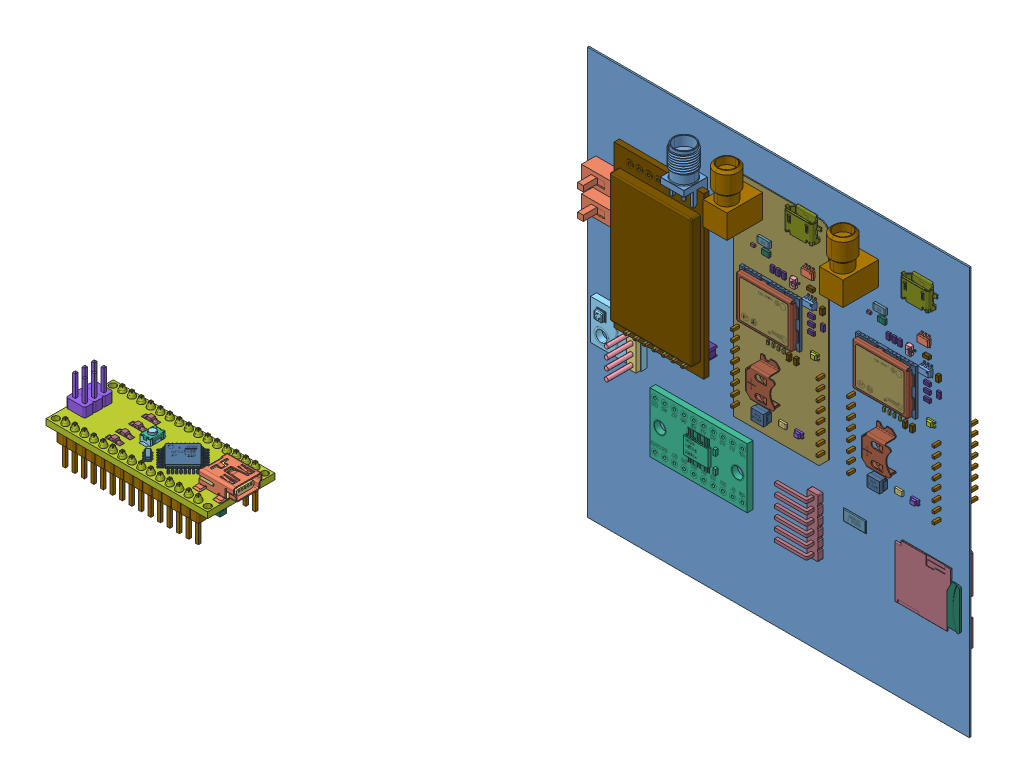
SolidWorks assembly PCB1, configuration Default. Lengths in mm.
Overall size (430.41 167.25 27.02).
258 component instances, 58 part files, 0 mates.
Components (placement in the parent):
- PCB1.step-1: PCB1.step [Default] at (36.6577 -60.7756 -25.2117) size (430.41 167.25 27.02)
  - Board.step-1: Board.step [Default] at origin size (102.11 108.97 0.41)
    - Open CASCADE STEP translator 6.8 2.1.1.step-1: Open CASCADE STEP translator 6.8 2.1.1.step [Default] at (0 0 -0.4115) size (102.11 108.97 0.41)
  - Arduino_Nano.step-1: Arduino_Nano.step [Default] at origin size (45 18.6 18)
    - MINIUSB_-_MEASURED.step-1: MINIUSB_-_MEASURED.step [Default] at (38.98 1.65 -7.62) x (0 0 1) z (-1 0 0) size (10.9 4.8 10.4)
      - MINIUSBSHELL.step-1: MINIUSBSHELL.step [Default] at origin size (10.9 3.75 9.4)
      - MINIUSBCORE.step-1: MINIUSBCORE.step [Default] at (0 0 6.7) x (-1 0 0) z (0 0 -1) size (7.7 4.5 8.2)
      - MINI_USB_CONTACT.step-1: MINI_USB_CONTACT.step [Default] at (-1.6 0 5.7) x (-1 0 0) z (0 0 -1) size (0.51 2.55 9.4)
      - MINI_USB_CONTACT.step-2: MINI_USB_CONTACT.step [Default] at (-0.8 0 5.7) x (-1 0 0) z (0 0 -1) size (0.51 2.55 9.4)
      - MINI_USB_CONTACT.step-3: MINI_USB_CONTACT.step [Default] at (0 0 5.7) x (-1 0 0) z (0 0 -1) size (0.51 2.55 9.4)
      - MINI_USB_CONTACT.step-4: MINI_USB_CONTACT.step [Default] at (0.8 0 5.7) x (-1 0 0) z (0 0 -1) size (0.51 2.55 9.4)
      - MINI_USB_CONTACT.step-5: MINI_USB_CONTACT.step [Default] at (1.6 0 5.7) x (-1 0 0) z (0 0 -1) size (0.51 2.55 9.4)
    - reset_button.step-1: reset_button.step [Default] at (15.25 1.6 -8.05) x (0 0 -1) z (1 0 0) size (5.2 2.15 3)
      - reset_core.step-1: reset_core.step [Default] at origin size (5.2 2.15 2.8)
      - reset_shell.step-1: reset_shell.step [Default] at (0 1.65 0) x (0 0 1) z (-1 0 0) size (3 1.65 4)
    - nano-board.step-1: nano-board.step [Default] at origin size (43.2 4.6 18)
    - 2pin_header__02.step-1: 2pin_header__02.step [Default] at (-1.143 1.6 -7.62) size (5 11.75 2.54)
    - 2pin_header__02.step-2: 2pin_header__02.step [Default] at (-1.143 1.6 -5.08) size (5 11.75 2.54)
    - 2pin_header__02.step-3: 2pin_header__02.step [Default] at (-1.143 1.6 -10.16) size (5 11.75 2.54)
    - 15pin_header__.step-1: 15pin_header__.step [Default] x (0 0 1) z (1 0 0) size (2.54 11.75 38.1)
    - 15pin_header__.step-2: 15pin_header__.step [Default] at (0 0 -15.24) x (0 0 1) z (1 0 0) size (2.54 11.75 38.1)
    - atmega328.step-1: atmega328.step [Default] at (23.85 1.75 -7.62) x (-0.707107 0 0.707107) z (-0.707107 0 -0.707107) size (10 1.1 10)
    - ftdi_FT232rl.step-1: ftdi_FT232rl.step [Default] at (29.05 0 -7.67) x (0 0 -1) z (-1 0 0) size (9.25 1.9 10.2)
    - smt_resistor222.step-1: smt_resistor222.step [Default] at (21.86 0 -5.8) x (0 0 -1) z (-1 0 0) size (1.7 0.6 3.8)
    - smt_resistor222.step-2: smt_resistor222.step [Default] at (21.86 0 -9) x (0 0 -1) z (-1 0 0) size (1.7 0.6 3.8)
    - smt_resistor222.step-3: smt_resistor222.step [Default] at (36.75 0 -7.6) x (0 0 -1) z (-1 0 0) size (1.7 0.6 3.8)
    - smt_resistor222.step-4: smt_resistor222.step [Default] at (36.75 0 -12) x (0 0 -1) z (-1 0 0) size (1.7 0.6 3.8)
    - smt_resistor222.step-5: smt_resistor222.step [Default] at (8.2 0 -2.6) x (0 0 -1) z (-1 0 0) size (1.7 0.6 3.8)
    - led.step-1: led.step [Default] at (10.4 1.6 -2.8) size (4 0.85 1.47)
    - led.step-2: led.step [Default] at (10.4 1.6 -5.55) size (4 0.85 1.47)
    - led.step-3: led.step [Default] at (10.4 1.6 -12.5) size (4 0.85 1.47)
    - led.step-4: led.step [Default] at (10.4 1.6 -9.05) size (4 0.85 1.47)
    - 16mhz_crystal_-_measured.step-1: 16mhz_crystal_-_measured.step [Default] at (18.5113 1.6 -3.5541) x (0.707107 0 0.707107) z (-0.707107 0 0.707107) size (3.4 0.8 2)
    - cap106C.step-1: cap106C.step [Default] at (37.2 0 -3.3) x (0 0 1) z (1 0 0) size (1.7 1.81 4)
    - cap106C.step-2: cap106C.step [Default] at (7.9 0 -5.6) x (0 0 -1) z (-1 0 0) size (1.7 1.81 4)
    - nano_-_reg.step-1: nano_-_reg.step [Default] at (6.1 0 -10.16) x (0 0 -1) z (-1 0 0) size (6.5 1.69 8.3)
    - NANO_DIODE.step-1: NANO_DIODE.step [Default] at (11.43 0 -4.2) x (0 0 1) z (1 0 0) size (4.92 1.39 1.7)
    - 189_RESISTOR_PACK.step-1: 189_RESISTOR_PACK.step [Default] at (15.75 0 -10.85) x (0 0 1) z (1 0 0) size (3.2 0.46 3)
    - 102_RESISTOR_PACK.step-1: 102_RESISTOR_PACK.step [Default] at (15.75 0 -5.2) x (0 0 1) z (1 0 0) size (3.2 0.46 3)
  - M0.step-1: M0.step [Default] at origin size (8.61 3.85 12.07)
    - SS12D00G4_1P2T_Straight.step-1: SS12D00G4_1P2T_Straight.step [Default] at (146.8249 131.405 2.54) x (1 0 0) z (0 0 1) size (8.61 3.85 12.07)
  - BMP.step-1: BMP.step [Default] at origin size (13.52 10.7 12.7)
    - 1185083472.step-1: 1185083472.step [Default] at (154.178 97.536 0) size (2.54 10.16 2.8)
      - Extruded.step-1: Extruded.step [Default] at origin size (2.54 10.16 2.8)
    - 1185083552.step-1: 1185083552.step [Default] at (154.1779 93.7261 -3.2) x (0 1 0) z (0 0 1) size (1.06 1.06 12.7)
      - Cylinder.step-1: Cylinder.step [Default] at origin size (1.06 1.06 12.7)
    - 1185083552.step-2: 1185083552.step [Default] at (154.1779 96.2661 -3.2) x (0 1 0) z (0 0 1) size (1.06 1.06 12.7)
      - Cylinder.step-1: Cylinder.step [Default] at origin size (1.06 1.06 12.7)
    - 1185083552.step-3: 1185083552.step [Default] at (154.1779 98.8061 -3.2) x (0 1 0) z (0 0 1) size (1.06 1.06 12.7)
      - Cylinder.step-1: Cylinder.step [Default] at origin size (1.06 1.06 12.7)
    - 1185083552.step-4: 1185083552.step [Default] at (154.1779 101.3461 -3.2) x (0 1 0) z (0 0 1) size (1.06 1.06 12.7)
      - Cylinder.step-1: Cylinder.step [Default] at origin size (1.06 1.06 12.7)
    - GY-BME280.step-1: GY-BME280.step [Default] at (155.5751 97.6629 0) x (0 1 0) z (0 0 1) size (10.7 13.52 3.64)
  - LVL_CONV.step-1: LVL_CONV.step [Default] at origin size (26 16 2.26)
    - TXS0108E.step-1: TXS0108E.step [Default] at (183.8961 73.6876 0) x (-1 0 0) z (0 1 0) size (26 2.26 16)
  - GPS.step-1: GPS.step [Default] at origin size (219.53 65.66 19.66)
    - GNSS_7_Click_v100_noAntenna.step-1: GNSS_7_Click_v100_noAntenna.step [Default] at (180.3023 96.7993 0.254) x (1 0 0) z (0 0 1) size (219.53 65.66 19.66)
      - GNSS_7_Click_v100.step.step-1: GNSS_7_Click_v100.step.step [Default] at origin size (219.53 65.66 19.66)
        - JP4.step.step-1: JP4.step.step [Default] at origin size (0.5 1 0.35)
          - User_Library-R_0402.step.step-1: User_Library-R_0402.step.step [Default] at (12.3191 18.1685 0) x (0 -1 0) z (0 0 1) size (1 0.5 0.35)
        - JP3.step.step-1: JP3.step.step [Default] at origin size (0.5 1 0.35)
          - User_Library-R_0402.step.step-1: User_Library-R_0402.step.step [Default] at (10.9221 18.161 0) x (0 -1 0) z (0 0 1) size (1 0.5 0.35)
        - JP2.step.step-1: JP2.step.step [Default] at origin size (0.5 1 0.35)
          - User_Library-R_0402.step.step-1: User_Library-R_0402.step.step [Default] at (9.5251 18.1685 0) x (0 -1 0) z (0 0 1) size (1 0.5 0.35)
        - JP1.step.step-1: JP1.step.step [Default] at origin size (0.5 1 0.35)
          - User_Library-R_0402.step.step-1: User_Library-R_0402.step.step [Default] at (8.1281 18.1685 0) x (0 -1 0) z (0 0 1) size (1 0.5 0.35)
        - MBD1.step.step-1: MBD1.step.step [Default] at origin size (25.78 20.32 12.19)
          - Header_1x8.step.step-1: Header_1x8.step.step [Default] at (-74.8548 -67.056 0) size (2.92 20.32 12.19)
            - PCB.step.step-1: PCB.step.step [Default] at origin size (2.92 20.32 12.19)
              - Free-Models.step.step-1: Free-Models.step.step [Default] at origin size (2.92 20.32 12.19)
                - 1240637040.step.step-1: 1240637040.step.step [Default] at (97.7778 84.836 -1.6002) x (0 -1 0) z (1 0 0) size (12.7 12.19 2.92)
                  - User_Library-PinHeaderX5-1_PinHeaderX5_Body_1.step.step-1: User_Library-PinHeaderX5-1_PinHeaderX5_Body_1.step.step [Default] at origin size (12.7 2.54 2.92)
                  - User_Library-PinHeaderX5-1_PinHeaderX5_Pins_1.step.step-1: User_Library-PinHeaderX5-1_PinHeaderX5_Pins_1.step.step [Default] at origin size (10.8 12.19 0.64)
                - 1240637040.step.step-2: 1240637040.step.step [Default] at (97.7778 77.216 -1.6002) x (0 -1 0) z (1 0 0) size (12.7 12.19 2.92)
                  - User_Library-PinHeaderX5-1_PinHeaderX5_Body_1.step.step-1: User_Library-PinHeaderX5-1_PinHeaderX5_Body_1.step.step [Default] at origin size (12.7 2.54 2.92)
                  - User_Library-PinHeaderX5-1_PinHeaderX5_Pins_1.step.step-1: User_Library-PinHeaderX5-1_PinHeaderX5_Pins_1.step.step [Default] at origin size (10.8 12.19 0.64)
          - Header_1x8.step.step-2: Header_1x8.step.step [Default] at (-97.7148 -67.056 0) size (2.92 20.32 12.19)
            - PCB.step.step-1: PCB.step.step [Default] at origin size (2.92 20.32 12.19)
              - Free-Models.step.step-1: Free-Models.step.step [Default] at origin size (2.92 20.32 12.19)
                - 1240637040.step.step-1: 1240637040.step.step [Default] at (97.7778 84.836 -1.6002) x (0 -1 0) z (1 0 0) size (12.7 12.19 2.92)
                  - User_Library-PinHeaderX5-1_PinHeaderX5_Body_1.step.step-1: User_Library-PinHeaderX5-1_PinHeaderX5_Body_1.step.step [Default] at origin size (12.7 2.54 2.92)
                  - User_Library-PinHeaderX5-1_PinHeaderX5_Pins_1.step.step-1: User_Library-PinHeaderX5-1_PinHeaderX5_Pins_1.step.step [Default] at origin size (10.8 12.19 0.64)
                - 1240637040.step.step-2: 1240637040.step.step [Default] at (97.7778 77.216 -1.6002) x (0 -1 0) z (1 0 0) size (12.7 12.19 2.92)
                  - User_Library-PinHeaderX5-1_PinHeaderX5_Body_1.step.step-1: User_Library-PinHeaderX5-1_PinHeaderX5_Body_1.step.step [Default] at origin size (12.7 2.54 2.92)
                  - User_Library-PinHeaderX5-1_PinHeaderX5_Pins_1.step.step-1: User_Library-PinHeaderX5-1_PinHeaderX5_Pins_1.step.step [Default] at origin size (10.8 12.19 0.64)
        - M1.step.step-1: M1.step.step [Default] at origin size (16 12.2 2.33)
          - NEO.step.step-1: NEO.step.step [Default] at (27.1803 74.1975 0.44) x (0 1 0) z (0 0 1) size (12.2 16 2.33)
            - NEO_PCB.step.step-1: NEO_PCB.step.step [Default] at (-47.5276 18.1124 -0.4125) size (12.2 16 0.9)
            - Shield_NEO.step.step-1: Shield_NEO.step.step [Default] at (-52.9276 25.2124 1.8175) x (0 -1 0) z (-1 0 0) size (15 1.4 11.6)
            - u-blox_NEO_label.step.step-1: u-blox_NEO_label.step.step [Default] at (-47.5276 18.1124 1.8175) x (0 1 0) z (1 0 0) size (13 0.06 10)
        - L1.step.step-1: L1.step.step [Default] at origin size (1 0.6 0.5)
          - User_Library-Chip_InductorINDC1005X60N.step.step-1: User_Library-Chip_InductorINDC1005X60N.step.step [Default] at (4.191 38.435 0.2433) x (1 0 0) z (0 0 1) size (1 0.6 0.5)
        - R9.step.step-1: R9.step.step [Default] at origin size (3.2 1.6 0.6)
          - User_Library-R_1206.step.step-1: User_Library-R_1206.step.step [Default] at (7.197 41.0209 0) x (-1 0 0) z (0 0 1) size (3.2 1.6 0.6)
        - C6.step.step-1: C6.step.step [Default] at origin size (2 1.25 0.6)
          - User_Library-SMD_CAPACITOR0805.step.step-1: User_Library-SMD_CAPACITOR0805.step.step [Default] at (7.7471 38.7351 0.3) x (1 0 0) z (0 -1 0) size (2 0.6 1.25)
        - CN1.step.step-1: CN1.step.step [Default] at origin size (219.53 5.57 3.04)
          - User_Library-10104110.step.step-1: User_Library-10104110.step.step [Default] at (18.415 48.7408 6.9215) x (-1 0 0) z (0 0 1) size (219.53 5.57 3.04)
        - R8.step.step-1: R8.step.step [Default] at origin size (1.6 0.9 0.5)
          - User_Library-R_0603.step.step-1: User_Library-R_0603.step.step [Default] at (19.8119 26.289 0) x (-1 0 0) z (0 0 1) size (1.6 0.9 0.5)
        - C3.step.step-1: C3.step.step [Default] at origin size (0.8 1.6 0.8)
          - User_Library-SMD_CAPACITOR0603.step.step-1: User_Library-SMD_CAPACITOR0603.step.step [Default] at (15.8749 17.7801 0.39) x (0 1 0) z (0 0 1) size (1.6 0.8 0.8)
        - C2.step.step-1: C2.step.step [Default] at origin size (0.8 1.6 0.8)
          - User_Library-SMD_CAPACITOR0603.step.step-1: User_Library-SMD_CAPACITOR0603.step.step [Default] at (13.9699 17.7801 0.39) x (0 1 0) z (0 0 1) size (1.6 0.8 0.8)
        - U2.step.step-1: U2.step.step [Default] at origin size (2.9 2.8 1.45)
          - User_Library-SOT23-5-2.step.step-1: User_Library-SOT23-5-2.step.step [Default] at (19.812 33.2739 0) x (-1 0 0) z (0 0 1) size (2.9 2.8 1.45)
        - U1.step.step-1: U1.step.step [Default] at origin size (2.9 2.82 1)
          - TSOT-23-6(S6).step.step-1: TSOT-23-6(S6).step.step [Default] at (19.1769 39.878 0) x (0 1 0) z (1 0 0) size (2.82 1 2.9)
        - R7.step.step-1: R7.step.step [Default] at origin size (0.9 1.6 0.5)
          - User_Library-R_0603.step.step-1: User_Library-R_0603.step.step [Default] at (12.446 35.8141 0) x (0 1 0) z (0 0 1) size (1.6 0.9 0.5)
        - R6.step.step-1: R6.step.step [Default] at origin size (0.9 1.6 0.5)
          - User_Library-R_0603.step.step-1: User_Library-R_0603.step.step [Default] at (10.922 35.8141 0) x (0 1 0) z (0 0 1) size (1.6 0.9 0.5)
        - R5.step.step-1: R5.step.step [Default] at origin size (0.9 1.6 0.5)
          - User_Library-R_0603.step.step-1: User_Library-R_0603.step.step [Default] at (9.398 35.8139 0) x (0 -1 0) z (0 0 1) size (1.6 0.9 0.5)
        - R4.step.step-1: R4.step.step [Default] at origin size (0.9 1.6 0.5)
          - User_Library-R_0603.step.step-1: User_Library-R_0603.step.step [Default] at (22.86 28.9559 0) x (0 -1 0) z (0 0 1) size (1.6 0.9 0.5)
        - R3.step.step-1: R3.step.step [Default] at origin size (1.6 0.9 0.5)
          - User_Library-R_0603.step.step-1: User_Library-R_0603.step.step [Default] at (19.8119 28.194 0) x (-1 0 0) z (0 0 1) size (1.6 0.9 0.5)
        - R2.step.step-1: R2.step.step [Default] at origin size (1.6 0.9 0.5)
          - User_Library-R_0603.step.step-1: User_Library-R_0603.step.step [Default] at (19.8119 30.099 0) x (-1 0 0) z (0 0 1) size (1.6 0.9 0.5)
        - R1.step.step-1: R1.step.step [Default] at origin size (2 1.25 0.5)
          - User_Library-R_0805.step.step-1: User_Library-R_0805.step.step [Default] at (12.1919 1.1429 0) x (-1 0 0) z (0 0 1) size (2 1.25 0.5)
        - Q1.step.step-1: Q1.step.step [Default] at origin size (2.25 2.2 1.1)
          - SOT323_(SC70-3)-1.step.step-1: SOT323_(SC70-3)-1.step.step [Default] at (15.3671 35.8141 0) x (0 -1 0) z (-1 0 0) size (2.2 1.1 2.25)
            - User_Library-SOT323_(SC70-3)-1_K_X_F6rper_1.step.step-1: User_Library-SOT323_(SC70-3)-1_K_X_F6rper_1.step.step [Default] x (0 0 -1) z (0 1 0) size (1.35 2.2 1)
            - User_Library-SOT323_(SC70-3)-1_Beschriftung_1.step.step-1: User_Library-SOT323_(SC70-3)-1_Beschriftung_1.step.step [Default] x (0 0 -1) z (0 1 0) size (0.8 1.45 0.06)
            - User_Library-SOT323_(SC70-3)-1_Pins_1.step.step-1: User_Library-SOT323_(SC70-3)-1_Pins_1.step.step [Default] at (0.65 0 0) x (0 0 1) z (0 1 0) size (0.6 0.4 0.9)
            - User_Library-SOT323_(SC70-3)-1_Pins_1.step.step-2: User_Library-SOT323_(SC70-3)-1_Pins_1.step.step [Default] at (-0.65 0 0) x (0 0 1) z (0 1 0) size (0.6 0.4 0.9)
            - User_Library-SOT323_(SC70-3)-1_Pins_1.step.step-3: User_Library-SOT323_(SC70-3)-1_Pins_1.step.step [Default] x (0 0 -1) z (0 1 0) size (0.6 0.4 0.9)
        - LD2.step.step-1: LD2.step.step [Default] at origin size (2.1 1.35 0.91)
          - CHIPLED-0805-RED.step.step-1: CHIPLED-0805-RED.step.step [Default] at (20.7009 21.3361 0) x (0 1 0) z (0 0 1) size (1.35 2.1 0.91)
        - LD1.step.step-1: LD1.step.step [Default] at origin size (2.02 1.25 1.1)
          - led_0805_green.step.step-1: led_0805_green.step.step [Default] at (16.5099 1.143 0) x (-1 0 0) z (0 0 1) size (2.02 1.25 1.1)
        - CN2.step.step-1: CN2.step.step [Default] at origin size (6.35 14.81 13.49)
          - User_Library-sma_ra_pcb_mount_molex.step.step-1: User_Library-sma_ra_pcb_mount_molex.step.step [Default] at (3.302 48.7682 0) x (0 1 0) z (0 0 1) size (14.81 6.35 13.49)
        - C5.step.step-1: C5.step.step [Default] at origin size (0.8 1.6 0.8)
          - User_Library-SMD_CAPACITOR0603.step.step-1: User_Library-SMD_CAPACITOR0603.step.step [Default] at (22.8791 32.8929 0.39) x (0 -1 0) z (0 0 1) size (1.6 0.8 0.8)
        - C4.step.step-1: C4.step.step [Default] at origin size (1.6 0.8 0.8)
          - User_Library-SMD_CAPACITOR0603.step.step-1: User_Library-SMD_CAPACITOR0603.step.step [Default] at (19.8121 36.4491 0.39) size (1.6 0.8 0.8)
        - C1.step.step-1: C1.step.step [Default] at origin size (3.7 2.93 2.03)
          - User_Library-AVX_BCASE.step.step-1: User_Library-AVX_BCASE.step.step [Default] at (7.0351 1.1431 0) x (1 0 0) z (0 0 1) size (3.7 2.93 2.03)
        - BAT1.step.step-1: BAT1.step.step [Default] at origin size (8 10.71 3.05)
          - keystone-PN2998TR.step.step-1: keystone-PN2998TR.step.step [Default] at (5.2705 9.272 2.9) x (0 -1 0) z (-1 0 0) size (10.71 3.05 8)
        - Board.step.step-1: Board.step.step [Default] at origin size (25.4 57.15 1.59)
  - GAL.step-1: GAL.step [Default] at origin size (219.53 65.66 19.66)
    - GNSS_7_Click_v100_noAntenna.step-1: GNSS_7_Click_v100_noAntenna.step [Default] at (211.1003 96.5199 0) x (1 0 0) z (0 0 1) size (219.53 65.66 19.66)
      - GNSS_7_Click_v100.step.step-1: GNSS_7_Click_v100.step.step [Default] at origin size (219.53 65.66 19.66)
        - JP4.step.step-1: JP4.step.step [Default] at origin size (0.5 1 0.35)
          - User_Library-R_0402.step.step-1: User_Library-R_0402.step.step [Default] at (12.3191 18.1685 0) x (0 -1 0) z (0 0 1) size (1 0.5 0.35)
        - JP3.step.step-1: JP3.step.step [Default] at origin size (0.5 1 0.35)
          - User_Library-R_0402.step.step-1: User_Library-R_0402.step.step [Default] at (10.9221 18.161 0) x (0 -1 0) z (0 0 1) size (1 0.5 0.35)
        - JP2.step.step-1: JP2.step.step [Default] at origin size (0.5 1 0.35)
          - User_Library-R_0402.step.step-1: User_Library-R_0402.step.step [Default] at (9.5251 18.1685 0) x (0 -1 0) z (0 0 1) size (1 0.5 0.35)
        - JP1.step.step-1: JP1.step.step [Default] at origin size (0.5 1 0.35)
          - User_Library-R_0402.step.step-1: User_Library-R_0402.step.step [Default] at (8.1281 18.1685 0) x (0 -1 0) z (0 0 1) size (1 0.5 0.35)
        - MBD1.step.step-1: MBD1.step.step [Default] at origin size (25.78 20.32 12.19)
          - Header_1x8.step.step-1: Header_1x8.step.step [Default] at (-74.8548 -67.056 0) size (2.92 20.32 12.19)
            - PCB.step.step-1: PCB.step.step [Default] at origin size (2.92 20.32 12.19)
              - Free-Models.step.step-1: Free-Models.step.step [Default] at origin size (2.92 20.32 12.19)
                - 1240637040.step.step-1: 1240637040.step.step [Default] at (97.7778 84.836 -1.6002) x (0 -1 0) z (1 0 0) size (12.7 12.19 2.92)
                  - User_Library-PinHeaderX5-1_PinHeaderX5_Body_1.step.step-1: User_Library-PinHeaderX5-1_PinHeaderX5_Body_1.step.step [Default] at origin size (12.7 2.54 2.92)
                  - User_Library-PinHeaderX5-1_PinHeaderX5_Pins_1.step.step-1: User_Library-PinHeaderX5-1_PinHeaderX5_Pins_1.step.step [Default] at origin size (10.8 12.19 0.64)
                - 1240637040.step.step-2: 1240637040.step.step [Default] at (97.7778 77.216 -1.6002) x (0 -1 0) z (1 0 0) size (12.7 12.19 2.92)
                  - User_Library-PinHeaderX5-1_PinHeaderX5_Body_1.step.step-1: User_Library-PinHeaderX5-1_PinHeaderX5_Body_1.step.step [Default] at origin size (12.7 2.54 2.92)
                  - User_Library-PinHeaderX5-1_PinHeaderX5_Pins_1.step.step-1: User_Library-PinHeaderX5-1_PinHeaderX5_Pins_1.step.step [Default] at origin size (10.8 12.19 0.64)
          - Header_1x8.step.step-2: Header_1x8.step.step [Default] at (-97.7148 -67.056 0) size (2.92 20.32 12.19)
            - PCB.step.step-1: PCB.step.step [Default] at origin size (2.92 20.32 12.19)
              - Free-Models.step.step-1: Free-Models.step.step [Default] at origin size (2.92 20.32 12.19)
                - 1240637040.step.step-1: 1240637040.step.step [Default] at (97.7778 84.836 -1.6002) x (0 -1 0) z (1 0 0) size (12.7 12.19 2.92)
                  - User_Library-PinHeaderX5-1_PinHeaderX5_Body_1.step.step-1: User_Library-PinHeaderX5-1_PinHeaderX5_Body_1.step.step [Default] at origin size (12.7 2.54 2.92)
                  - User_Library-PinHeaderX5-1_PinHeaderX5_Pins_1.step.step-1: User_Library-PinHeaderX5-1_PinHeaderX5_Pins_1.step.step [Default] at origin size (10.8 12.19 0.64)
                - 1240637040.step.step-2: 1240637040.step.step [Default] at (97.7778 77.216 -1.6002) x (0 -1 0) z (1 0 0) size (12.7 12.19 2.92)
                  - User_Library-PinHeaderX5-1_PinHeaderX5_Body_1.step.step-1: User_Library-PinHeaderX5-1_PinHeaderX5_Body_1.step.step [Default] at origin size (12.7 2.54 2.92)
                  - User_Library-PinHeaderX5-1_PinHeaderX5_Pins_1.step.step-1: User_Library-PinHeaderX5-1_PinHeaderX5_Pins_1.step.step [Default] at origin size (10.8 12.19 0.64)
        - M1.step.step-1: M1.step.step [Default] at origin size (16 12.2 2.33)
          - NEO.step.step-1: NEO.step.step [Default] at (27.1803 74.1975 0.44) x (0 1 0) z (0 0 1) size (12.2 16 2.33)
            - NEO_PCB.step.step-1: NEO_PCB.step.step [Default] at (-47.5276 18.1124 -0.4125) size (12.2 16 0.9)
            - Shield_NEO.step.step-1: Shield_NEO.step.step [Default] at (-52.9276 25.2124 1.8175) x (0 -1 0) z (-1 0 0) size (15 1.4 11.6)
            - u-blox_NEO_label.step.step-1: u-blox_NEO_label.step.step [Default] at (-47.5276 18.1124 1.8175) x (0 1 0) z (1 0 0) size (13 0.06 10)
        - L1.step.step-1: L1.step.step [Default] at origin size (1 0.6 0.5)
          - User_Library-Chip_InductorINDC1005X60N.step.step-1: User_Library-Chip_InductorINDC1005X60N.step.step [Default] at (4.191 38.435 0.2433) x (1 0 0) z (0 0 1) size (1 0.6 0.5)
        - R9.step.step-1: R9.step.step [Default] at origin size (3.2 1.6 0.6)
          - User_Library-R_1206.step.step-1: User_Library-R_1206.step.step [Default] at (7.197 41.0209 0) x (-1 0 0) z (0 0 1) size (3.2 1.6 0.6)
        - C6.step.step-1: C6.step.step [Default] at origin size (2 1.25 0.6)
          - User_Library-SMD_CAPACITOR0805.step.step-1: User_Library-SMD_CAPACITOR0805.step.step [Default] at (7.7471 38.7351 0.3) x (1 0 0) z (0 -1 0) size (2 0.6 1.25)
        - CN1.step.step-1: CN1.step.step [Default] at origin size (219.53 5.57 3.04)
          - User_Library-10104110.step.step-1: User_Library-10104110.step.step [Default] at (18.415 48.7408 6.9215) x (-1 0 0) z (0 0 1) size (219.53 5.57 3.04)
        - R8.step.step-1: R8.step.step [Default] at origin size (1.6 0.9 0.5)
          - User_Library-R_0603.step.step-1: User_Library-R_0603.step.step [Default] at (19.8119 26.289 0) x (-1 0 0) z (0 0 1) size (1.6 0.9 0.5)
        - C3.step.step-1: C3.step.step [Default] at origin size (0.8 1.6 0.8)
          - User_Library-SMD_CAPACITOR0603.step.step-1: User_Library-SMD_CAPACITOR0603.step.step [Default] at (15.8749 17.7801 0.39) x (0 1 0) z (0 0 1) size (1.6 0.8 0.8)
        - C2.step.step-1: C2.step.step [Default] at origin size (0.8 1.6 0.8)
          - User_Library-SMD_CAPACITOR0603.step.step-1: User_Library-SMD_CAPACITOR0603.step.step [Default] at (13.9699 17.7801 0.39) x (0 1 0) z (0 0 1) size (1.6 0.8 0.8)
        - U2.step.step-1: U2.step.step [Default] at origin size (2.9 2.8 1.45)
          - User_Library-SOT23-5-2.step.step-1: User_Library-SOT23-5-2.step.step [Default] at (19.812 33.2739 0) x (-1 0 0) z (0 0 1) size (2.9 2.8 1.45)
        - U1.step.step-1: U1.step.step [Default] at origin size (2.9 2.82 1)
          - TSOT-23-6(S6).step.step-1: TSOT-23-6(S6).step.step [Default] at (19.1769 39.878 0) x (0 1 0) z (1 0 0) size (2.82 1 2.9)
        - R7.step.step-1: R7.step.step [Default] at origin size (0.9 1.6 0.5)
          - User_Library-R_0603.step.step-1: User_Library-R_0603.step.step [Default] at (12.446 35.8141 0) x (0 1 0) z (0 0 1) size (1.6 0.9 0.5)
        - R6.step.step-1: R6.step.step [Default] at origin size (0.9 1.6 0.5)
          - User_Library-R_0603.step.step-1: User_Library-R_0603.step.step [Default] at (10.922 35.8141 0) x (0 1 0) z (0 0 1) size (1.6 0.9 0.5)
        - R5.step.step-1: R5.step.step [Default] at origin size (0.9 1.6 0.5)
          - User_Library-R_0603.step.step-1: User_Library-R_0603.step.step [Default] at (9.398 35.8139 0) x (0 -1 0) z (0 0 1) size (1.6 0.9 0.5)
        - R4.step.step-1: R4.step.step [Default] at origin size (0.9 1.6 0.5)
          - User_Library-R_0603.step.step-1: User_Library-R_0603.step.step [Default] at (22.86 28.9559 0) x (0 -1 0) z (0 0 1) size (1.6 0.9 0.5)
        - R3.step.step-1: R3.step.step [Default] at origin size (1.6 0.9 0.5)
          - User_Library-R_0603.step.step-1: User_Library-R_0603.step.step [Default] at (19.8119 28.194 0) x (-1 0 0) z (0 0 1) size (1.6 0.9 0.5)
        - R2.step.step-1: R2.step.step [Default] at origin size (1.6 0.9 0.5)
          - User_Library-R_0603.step.step-1: User_Library-R_0603.step.step [Default] at (19.8119 30.099 0) x (-1 0 0) z (0 0 1) size (1.6 0.9 0.5)
        - R1.step.step-1: R1.step.step [Default] at origin size (2 1.25 0.5)
          - User_Library-R_0805.step.step-1: User_Library-R_0805.step.step [Default] at (12.1919 1.1429 0) x (-1 0 0) z (0 0 1) size (2 1.25 0.5)
        - Q1.step.step-1: Q1.step.step [Default] at origin size (2.25 2.2 1.1)
          - SOT323_(SC70-3)-1.step.step-1: SOT323_(SC70-3)-1.step.step [Default] at (15.3671 35.8141 0) x (0 -1 0) z (-1 0 0) size (2.2 1.1 2.25)
            - User_Library-SOT323_(SC70-3)-1_K_X_F6rper_1.step.step-1: User_Library-SOT323_(SC70-3)-1_K_X_F6rper_1.step.step [Default] x (0 0 -1) z (0 1 0) size (1.35 2.2 1)
            - User_Library-SOT323_(SC70-3)-1_Beschriftung_1.step.step-1: User_Library-SOT323_(SC70-3)-1_Beschriftung_1.step.step [Default] x (0 0 -1) z (0 1 0) size (0.8 1.45 0.06)
            - User_Library-SOT323_(SC70-3)-1_Pins_1.step.step-1: User_Library-SOT323_(SC70-3)-1_Pins_1.step.step [Default] at (0.65 0 0) x (0 0 1) z (0 1 0) size (0.6 0.4 0.9)
            - User_Library-SOT323_(SC70-3)-1_Pins_1.step.step-2: User_Library-SOT323_(SC70-3)-1_Pins_1.step.step [Default] at (-0.65 0 0) x (0 0 1) z (0 1 0) size (0.6 0.4 0.9)
            - User_Library-SOT323_(SC70-3)-1_Pins_1.step.step-3: User_Library-SOT323_(SC70-3)-1_Pins_1.step.step [Default] x (0 0 -1) z (0 1 0) size (0.6 0.4 0.9)
        - LD2.step.step-1: LD2.step.step [Default] at origin size (2.1 1.35 0.91)
          - CHIPLED-0805-RED.step.step-1: CHIPLED-0805-RED.step.step [Default] at (20.7009 21.3361 0) x (0 1 0) z (0 0 1) size (1.35 2.1 0.91)
        - LD1.step.step-1: LD1.step.step [Default] at origin size (2.02 1.25 1.1)
          - led_0805_green.step.step-1: led_0805_green.step.step [Default] at (16.5099 1.143 0) x (-1 0 0) z (0 0 1) size (2.02 1.25 1.1)
        - CN2.step.step-1: CN2.step.step [Default] at origin size (6.35 14.81 13.49)
          - User_Library-sma_ra_pcb_mount_molex.step.step-1: User_Library-sma_ra_pcb_mount_molex.step.step [Default] at (3.302 48.7682 0) x (0 1 0) z (0 0 1) size (14.81 6.35 13.49)
        - C5.step.step-1: C5.step.step [Default] at origin size (0.8 1.6 0.8)
          - User_Library-SMD_CAPACITOR0603.step.step-1: User_Library-SMD_CAPACITOR0603.step.step [Default] at (22.8791 32.8929 0.39) x (0 -1 0) z (0 0 1) size (1.6 0.8 0.8)
        - C4.step.step-1: C4.step.step [Default] at origin size (1.6 0.8 0.8)
          - User_Library-SMD_CAPACITOR0603.step.step-1: User_Library-SMD_CAPACITOR0603.step.step [Default] at (19.8121 36.4491 0.39) size (1.6 0.8 0.8)
        - C1.step.step-1: C1.step.step [Default] at origin size (3.7 2.93 2.03)
          - User_Library-AVX_BCASE.step.step-1: User_Library-AVX_BCASE.step.step [Default] at (7.0351 1.1431 0) x (1 0 0) z (0 0 1) size (3.7 2.93 2.03)
        - BAT1.step.step-1: BAT1.step.step [Default] at origin size (8 10.71 3.05)
          - keystone-PN2998TR.step.step-1: keystone-PN2998TR.step.step [Default] at (5.2705 9.272 2.9) x (0 -1 0) z (-1 0 0) size (10.71 3.05 8)
        - Board.step.step-1: Board.step.step [Default] at origin size (25.4 57.15 1.59)
  - M1.step-1: M1.step [Default] at origin size (8.61 3.85 12.07)
    - SS12D00G4_1P2T_Straight.step-1: SS12D00G4_1P2T_Straight.step [Default] at (146.8249 124.547 2.54) x (1 0 0) z (0 0 1) size (8.61 3.85 12.07)
  - SD.step-1: SD.step [Default] at origin size (46.9 24 6.7)
    - MicroSD_Reader_Assembly.step-1: MicroSD_Reader_Assembly.step [Default] at (210.8201 82.6769 0.127) x (-1 0 0) z (0 0 1) size (46.9 24 6.7)
      - sdreader.step-1: sdreader.step [Default] at (-11.2744 2.632 -3.2) size (46.9 24 6.7)
        - Open CASCADE STEP translator 6.8 2.9.1.1.1.step-1: Open CASCADE STEP translator 6.8 2.9.1.1.1.step [Default] at origin size (46.9 24 6.7)
        - Open CASCADE STEP translator 6.8 2.9.1.1.2.step-1: Open CASCADE STEP translator 6.8 2.9.1.1.2.step [Default] at origin
      - AMS1117.step-1: AMS1117.step [Default] at (-0.4339 -2.128 -1.13) x (1 0 0) z (0 -1 0) size (6.51 1.86 7)
      - card_sd.step-1: card_sd.step [Default] at (-21.187 5.4466 -0.36) x (0 -1 0) z (0 0 1) size (11 15 0.82)
  - LoRA_-_ES32.step-1: LoRA_-_ES32.step [Default] at origin size (24 52.5 13.5)
    - STEP-7pin-61300711121-rev1.step-1: STEP-7pin-61300711121-rev1.step [Default] at (165.6081 105.664 1.2975) x (1 0 0) z (0 -1 0) size (17.78 11.54 2.54)
      - 6130xx11121_PIN.step-1: 6130xx11121_PIN.step [Default] at (-7.62 1.5 0) x (1 0 0) z (0 -1 0) size (0.64 0.64 11.54)
      - 6130xx11121_PIN.step-2: 6130xx11121_PIN.step [Default] at (-5.08 1.5 0) x (1 0 0) z (0 -1 0) size (0.64 0.64 11.54)
      - 6130xx11121_PIN.step-3: 6130xx11121_PIN.step [Default] at (-2.54 1.5 0) x (1 0 0) z (0 -1 0) size (0.64 0.64 11.54)
      - 6130xx11121_PIN.step-4: 6130xx11121_PIN.step [Default] at (0 1.5 0) x (1 0 0) z (0 -1 0) size (0.64 0.64 11.54)
      - 6130xx11121_PIN.step-5: 6130xx11121_PIN.step [Default] at (2.54 1.5 0) x (1 0 0) z (0 -1 0) size (0.64 0.64 11.54)
      - 6130xx11121_PIN.step-6: 6130xx11121_PIN.step [Default] at (5.08 1.5 0) x (1 0 0) z (0 -1 0) size (0.64 0.64 11.54)
      - 6130xx11121_PIN.step-7: 6130xx11121_PIN.step [Default] at (7.62 1.5 0) x (1 0 0) z (0 -1 0) size (0.64 0.64 11.54)
      - 61300711121.step-1: 61300711121.step [Default] at origin size (17.78 2.54 2.54)
    - E32-TTL.step-1: E32-TTL.step [Default] at (165.6386 192.5439 25.4) x (0 1 0) z (1 0 0) size (52.5 13.5 24)
      - E32-TTL-1W_Predeterminado.step-1: E32-TTL-1W_Predeterminado.step [Default] at (-66.873 -19.9517 0) size (43 3.79 24)
      - SMA_CONNECTOR_-_EMPCB.SMAFSTJ.B.HT.step-1: SMA_CONNECTOR_-_EMPCB.SMAFSTJ.B.HT.step [Default] at (-43.773 -15.0017 10.2201) x (0 0 1) z (1 0 0) size (6.58 6.35 13.3)
      - 05__HEADER-3WAY-1ROW-2.54MM-VERTICAL-PCB_Predeterminado.step-1: 05__HEADER-3WAY-1ROW-2.54MM-VERTICAL-PCB_Predeterminado.step [Default] at (-87.6961 -24.2405 2.52) x (0 -1 0) z (0 0 1) size (11.55 2.54 7.62)
      - 05__HEADER-3WAY-1ROW-2.54MM-VERTICAL-PCB_Predeterminado.step-2: 05__HEADER-3WAY-1ROW-2.54MM-VERTICAL-PCB_Predeterminado.step [Default] at (-87.6961 -24.2405 -5.1) x (0 -1 0) z (0 0 1) size (11.55 2.54 7.62)
      - HEADER-1WAY-1ROW-2.54MM-VERTICAL-PCB_Predeterminado.step-1: HEADER-1WAY-1ROW-2.54MM-VERTICAL-PCB_Predeterminado.step [Default] at (-86.893 -19.9517 -7.64) x (0 -1 0) z (-1 0 0) size (11.54 2.54 2.54)
